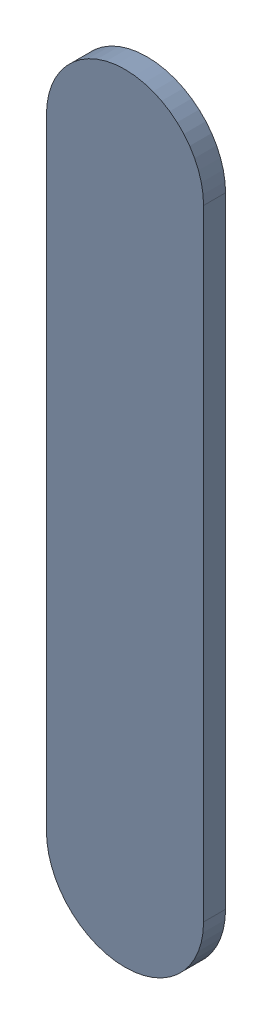
SolidWorks assembly Track (23mm,54.9mm)(23mm,55.903mm) on Top Layer, configuration Predeterminado. Lengths in mm.
Overall size (0.25 1.26 0.04).
2 component instances, 1 part files, 0 mates.
Components (placement in the parent):
- Track (23mm,54.9mm)(23mm,55.903mm) on Top Layer-1-1: Track (23mm,54.9mm)(23mm,55.903mm) on Top Layer-1 [Predeterminado] at (-68.317 -44.187 -0.0457) size (0.25 1.26 0.04)
  - Track (23mm,54.9mm)(23mm,55.903mm) on Top Layer-Part-1-1: Track (23mm,54.9mm)(23mm,55.903mm) on Top Layer-Part-1 [Predeterminado] at origin size (0.25 1.26 0.04)
